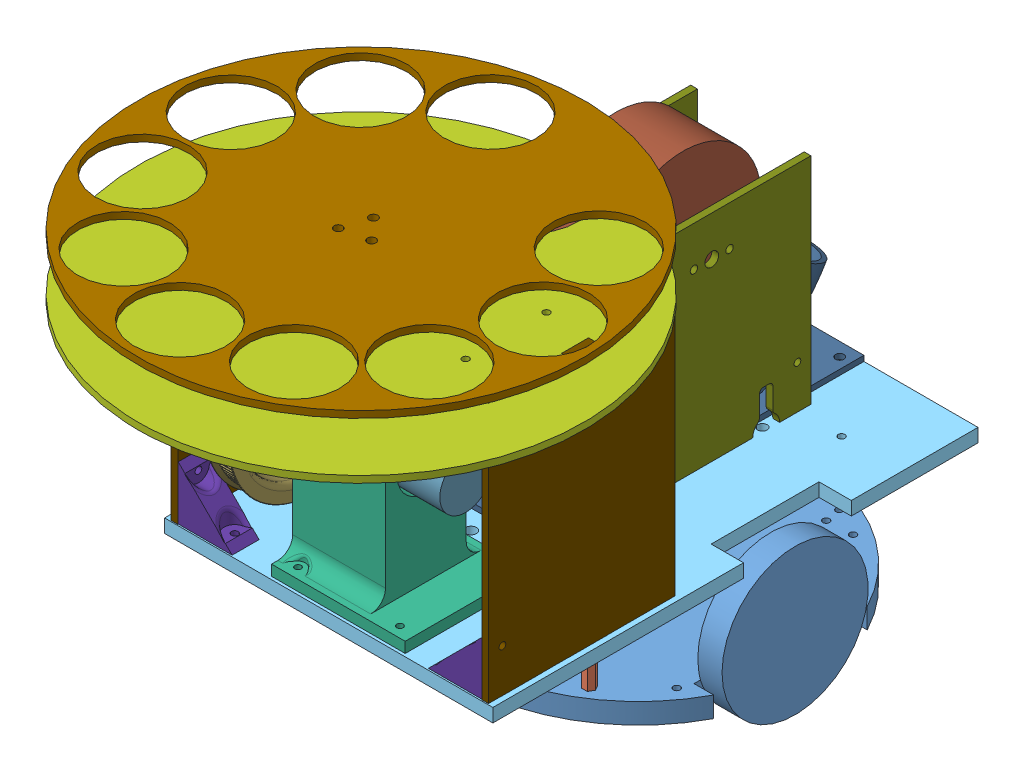
SolidWorks assembly car_and_shooter_assem, configuration Default. Lengths in mm.
Overall size (250.24 223.88 338.47).
32 component instances, 19 part files, 49 mates.
Components (placement in the parent):
- RSLKAss-1: RSLKAss [Default] at (33.1567 -8.9393 20.9388) size (154.69 155.83 228.6)
  - RSLKRobot-1: RSLKRobot [Default] at (-48.6373 76.7378 171.8377) size (153.54 68.83 162.51)
  - 1inHexSpacer-1: 1inHexSpacer [Default] at (-16.032 111.7898 197.7688) x (0.5 0 0.866025) z (0.866025 0 -0.5) size (5.57 31.75 4.83)
  - 1inHexSpacer-3: 1inHexSpacer [Default] at (67.9824 111.7898 197.7688) x (0.5 0 0.866025) z (0.866025 0 -0.5) size (5.57 31.75 4.83)
  - .75inHexSpacer-1: .75inHexSpacer [Default] at (52.5182 129.7222 100.832) x (1 0 0) z (0 0 -1) size (5.57 25.4 4.83)
  - .75inHexSpacer-2: .75inHexSpacer [Default] at (-0.5678 129.7222 191.0274) x (1 0 0) z (0 0 -1) size (5.57 25.4 4.83)
  - .75inHexSpacer-3: .75inHexSpacer [Default] at (52.5182 129.7222 191.0274) x (1 0 0) z (0 0 -1) size (5.57 25.4 4.83)
  - .75inHexSpacer-4: .75inHexSpacer [Default] at (-0.5678 129.7222 100.832) x (1 0 0) z (0 0 -1) size (5.57 25.4 4.83)
  - 1inHexSpacer-4: 1inHexSpacer [Default] at (-2.6646 111.7898 204.6548) x (0.5 0 0.866025) z (0.866025 0 -0.5) size (5.57 31.75 4.83)
  - 1inHexSpacer-5: 1inHexSpacer [Default] at (54.615 111.7898 204.6548) x (0.5 0 0.866025) z (0.866025 0 -0.5) size (5.57 31.75 4.83)
  - RSLKSpacePlate-1: RSLKSpacePlate [Default] at (67.9824 114.9648 197.7688) x (-1 0 0) z (0 0 -1) size (108.14 17.78 33.54)
  - RSLKBasePlate-2: RSLKBasePlate [Default] at (-0.5678 129.7222 191.276) size (154.69 6.35 228.6)
  - MotorMount-1: MotorMount [Default] at (-2.3457 191.0722 248.282) x (0 -1 0) z (1 0 0) size (81 58 63)
- bottom_plate-1: bottom_plate [Default] at (59.1391 246.5129 284.3207) size (210 3.17 210)
- stepper_motor_shaft-1: stepper_motor_shaft [Default] at (59.1391 249.6879 284.3207) x (0.976606 0 -0.215035) z (0.215035 0 0.976606) size (25.4 23.32 25.4)
- top_plate-1: top_plate [Default] at (59.1391 273.0079 284.3207) x (0.976606 0 -0.215035) z (0.215035 0 0.976606) size (210 3.17 210)
- ramp2-1: ramp2 [Default] at (59.1391 152.5329 147.1707) x (-1 0 0) z (0 0 -1) size (49.78 107.95 158.24)
- new_flywheel-1: new_flywheel [Default] at (41.8991 209.6829 147.1707) x (1 0 0) z (0 0.924409 -0.381402) size (36.83 73.66 73.66)
- BigBeltPulley-1: BigBeltPulley [Default] at (12.9611 182.1329 269.2207) x (0 0.970698 -0.240304) z (0 -0.240304 -0.970698) size (80.29 17.85 80.29)
- SmallBeltPulley-1: SmallBeltPulley [Default] at (13.4611 209.6829 147.1707) x (0 -0.048317 0.998832) z (0 0.998832 0.048317) size (23.29 19.9 23.29)
- dc_motor-1: dc_motor [Default] at (93.3111 182.1329 269.2207) x (-1 0 0) z (0 -0.970698 0.240304) size (75 32.2 24.4)
- ball-1: ball [Default] at (57.6426 155.7751 129.0822) x (-0.965872 0.249129 -0.070899) z (-0.118817 -0.182919 0.975922) size (42.67 42.67 42.67)
- SideFrameRight-1: SideFrameRight [Default] at (87.7141 127.1329 278.7427) x (0 0 1) z (-1 0 0) size (139.7 107.81 3.17)
- SideFrameRight-2: SideFrameRight [Default] at (33.7391 127.1329 278.2347) x (0 0 1) z (-1 0 0) size (139.7 107.81 3.17)
- 90Support-1: 90Support [Default] at (30.5641 127.1329 240.1347) x (0 0 -1) z (0 -1 0) size (13.26 25.4 25.4)
- wood_panel-1: wood_panel [Default] at (-12.4961 127.1329 211.2041) x (-1 0 0) z (0 0 -1) size (3.17 128.91 87.88)
- wood_panel-2: wood_panel [Default] at (133.8841 127.1329 211.1533) x (-1 0 0) z (0 0 -1) size (3.17 128.91 87.88)
- 90Support-2: 90Support [Default] at (-12.4961 246.5129 241.9381) x (0 0 1) z (-1 0 0) size (13.26 25.4 25.4)
- 90Support-3: 90Support [Default] at (-12.4961 127.1329 286.1741) x (0 0 1) z (0 -1 0) size (13.26 25.4 25.4)
- 90Support-4: 90Support [Default] at (130.7091 246.5129 292.6873) x (0 0 -1) z (1 0 0) size (13.26 25.4 25.4)
- 90Support-5: 90Support [Default] at (130.7091 127.1329 298.8233) x (0 0 -1) z (0 -1 0) size (13.26 25.4 25.4)
- shaft_for_motor_qtr_in-1: shaft_for_motor_qtr_in [Default] at (10.4611 209.6829 147.1707) size (71.12 6.22 6.22)
Mates (geometry in assembly coordinates):
- Concentric1: concentric aligned: cylinder of stepper_motor_shaft-1 through (53.5136 273.0079 289.4606) axis (0 -1 0) radius 1.875; cylinder of top_plate-1 through (53.5136 276.1829 289.4606) axis (0 -1 0) radius 2
- Concentric2: concentric aligned: cylinder of stepper_motor_shaft-1 through (66.4031 273.0079 286.6226) axis (0 -1 0) radius 1.875; cylinder of top_plate-1 through (66.4031 276.1829 286.6226) axis (0 -1 0) radius 2
- Coincident1: coincident anti-aligned: plane of stepper_motor_shaft-1 through (59.1391 273.0079 284.3207) normal (0 1 0); plane of top_plate-1 through (59.1391 273.0079 284.3207) normal (0 -1 0)
- Concentric3: concentric aligned: cylinder of bottom_plate-1 through (59.1391 249.6879 284.3207) axis (0 -1 0) radius 5; cylinder of stepper_motor_shaft-1 through (59.1391 270.0079 284.3207) axis (0 -1 0) radius 4.5
- Coincident2: coincident anti-aligned: plane of bottom_plate-1 through (59.1391 249.6879 284.3207) normal (0 1 0); plane of stepper_motor_shaft-1 through (59.1391 249.6879 284.3207) normal (0 -1 0)
- Coincident4: coincident anti-aligned: plane of RSLKAss-1/RSLKBasePlate-2 through (32.5889 127.1329 212.2148) normal (0 1 0); plane of ramp2-1 through (59.1391 127.1329 147.1707) normal (0 -1 0)
- Parallel2: parallel aligned: plane of RSLKAss-1/RSLKBasePlate-2 through (-18.2111 127.1329 70.9707) normal (0 0 -1); plane of ramp2-1 through (83.9991 127.1329 70.9707) normal (0 0 -1)
- Concentric4: concentric aligned: cylinder of bottom_plate-1 through (59.1391 249.6879 204.3207) axis (0 -1 0) radius 21.75; circle of ramp2-1
- Concentric5: concentric anti-aligned: circle of ramp2-1; cylinder of new_flywheel-1 through (80.7611 209.6829 147.1707) axis (-1 0 0) radius 36.83
- Distance1: distance = 7.62 mm: point of ramp2-1; plane of new_flywheel-1 through (41.8991 209.6829 147.1707) normal (-1 0 0)
- Concentric6: concentric aligned: cylinder of new_flywheel-1 through (80.7611 209.6829 147.1707) axis (-1 0 0) radius 36.83; cylinder of SmallBeltPulley-1 through (30.3611 209.6829 147.1707) axis (-1 0 0) radius 6.35
- Concentric7: concentric aligned: cylinder of RSLKAss-1/MotorMount-1 through (93.8111 182.1329 269.2207) axis (-1 0 0) radius 13.5; cylinder of BigBeltPulley-1 through (28.3111 182.1329 269.2207) axis (-1 0 0) radius 7.5
- Coincident5: coincident aligned: plane of BigBeltPulley-1 through (10.4611 182.1329 269.2207) normal (-1 0 0); plane of SmallBeltPulley-1 through (10.4611 209.6829 147.1707) normal (-1 0 0)
- Concentric8: concentric anti-aligned: cylinder of RSLKAss-1/MotorMount-1 through (93.8111 182.1329 269.2207) axis (-1 0 0) radius 13.5; cylinder of dc_motor-1 through (30.8111 182.1329 269.2207) axis (1 0 0) radius 12.2
- Coincident6: coincident aligned: plane of RSLKAss-1/MotorMount-1 through (30.8111 182.1329 269.2207) normal (-1 0 0); plane of dc_motor-1 through (30.8111 182.1329 269.2207) normal (-1 0 0)
- Parallel3: parallel anti-aligned: plane of BigBeltPulley-1 through (10.4611 183.0628 267.3937) normal (0 0.240304 0.970698); plane of dc_motor-1 through (18.3111 180.4884 268.0826) normal (0 -0.240304 -0.970698)
- Tangent1: tangent anti-aligned: torus of ramp2-1; sphere of ball-1
- Coincident7: coincident anti-aligned: plane of RSLKAss-1/RSLKBasePlate-2 through (84.5391 118.8779 202.5427) normal (0 0 -1); plane of SideFrameRight-1 through (84.5391 127.1329 202.5427) normal (0 0 1)
- Coincident8: coincident anti-aligned: plane of RSLKAss-1/RSLKBasePlate-2 through (32.5889 127.1329 212.2148) normal (0 1 0); plane of SideFrameRight-1 through (84.5391 127.1329 278.7427) normal (0 -1 0)
- Coincident9: coincident anti-aligned: plane of RSLKAss-1/RSLKBasePlate-2 through (84.5391 118.8779 184.0007) normal (1 0 0); plane of SideFrameRight-1 through (84.5391 127.1329 278.7427) normal (-1 0 0)
- Coincident10: coincident anti-aligned: plane of RSLKAss-1/RSLKBasePlate-2 through (30.6911 118.8779 202.0347) normal (0 0 -1); plane of SideFrameRight-2 through (30.5641 127.1329 202.0347) normal (0 0 1)
- Coincident11: coincident anti-aligned: plane of RSLKAss-1/RSLKBasePlate-2 through (32.5889 127.1329 212.2148) normal (0 1 0); plane of SideFrameRight-2 through (30.5641 127.1329 278.2347) normal (0 -1 0)
- Coincident12: coincident anti-aligned: plane of RSLKAss-1/RSLKBasePlate-2 through (33.7391 118.8779 202.0347) normal (-1 0 0); plane of SideFrameRight-2 through (33.7391 127.1329 278.2347) normal (1 0 0)
- Concentric9: concentric anti-aligned: cylinder of SideFrameRight-2 through (26.1191 147.4529 233.7847) axis (1 0 0) radius 1.5875; cylinder of 90Support-1 through (46.4391 147.4529 233.7847) axis (-1 0 0) radius 1.5875
- Coincident13: coincident anti-aligned: plane of RSLKAss-1/RSLKBasePlate-2 through (32.5889 127.1329 212.2148) normal (0 1 0); plane of 90Support-1 through (30.5641 127.1329 227.4347) normal (0 -1 0)
- Coincident14: coincident anti-aligned: plane of SideFrameRight-2 through (30.5641 127.1329 278.2347) normal (-1 0 0); plane of 90Support-1 through (30.5641 127.1329 227.4347) normal (1 0 0)
- Coincident16: coincident anti-aligned: plane of BigBeltPulley-1 through (28.3111 182.1329 269.2207) normal (1 0 0); plane of dc_motor-1 through (28.3111 182.1329 269.2207) normal (-1 0 0)
- Coincident17: coincident aligned: plane of RSLKAss-1/RSLKBasePlate-2 through (-18.2111 127.1329 70.9707) normal (0 0 -1); plane of ramp2-1 through (83.9991 127.1329 70.9707) normal (0 0 -1)
- Coincident18: coincident anti-aligned: plane of RSLKAss-1/RSLKBasePlate-2 through (-15.6711 120.7829 292.7127) normal (0 0 -1); plane of wood_panel-1 through (-15.6711 127.1329 292.7127) normal (0 0 1)
- Coincident19: coincident anti-aligned: plane of RSLKAss-1/RSLKBasePlate-2 through (-15.6711 120.7829 274.1707) normal (1 0 0); plane of wood_panel-1 through (-15.6711 127.1329 211.2041) normal (-1 0 0)
- Coincident20: coincident anti-aligned: plane of RSLKAss-1/RSLKBasePlate-2 through (32.5889 127.1329 212.2148) normal (0 1 0); plane of wood_panel-1 through (-15.6711 127.1329 211.2041) normal (0 -1 0)
- Coincident21: coincident anti-aligned: plane of RSLKAss-1/RSLKBasePlate-2 through (133.9349 120.7829 242.9287) normal (0 0 1); plane of wood_panel-2 through (130.7091 127.1329 242.9287) normal (0 0 -1)
- Coincident22: coincident anti-aligned: plane of RSLKAss-1/RSLKBasePlate-2 through (130.7091 120.7829 242.9287) normal (1 0 0); plane of wood_panel-2 through (130.7091 127.1329 211.1533) normal (-1 0 0)
- Coincident23: coincident anti-aligned: plane of RSLKAss-1/RSLKBasePlate-2 through (32.5889 127.1329 212.2148) normal (0 1 0); plane of wood_panel-2 through (130.7091 127.1329 292.6619) normal (0 -1 0)
- Concentric10: concentric anti-aligned: cylinder of wood_panel-1 through (-12.4961 226.1929 248.2881) axis (-1 0 0) radius 1.5875; cylinder of 90Support-2 through (-28.3711 226.1929 248.2881) axis (1 0 0) radius 1.5875
- Coincident24: coincident anti-aligned: plane of wood_panel-1 through (-12.4961 127.1329 211.2041) normal (1 0 0); plane of 90Support-2 through (-12.4961 246.5129 254.6381) normal (-1 0 0)
- Parallel4: parallel aligned: plane of wood_panel-1 through (-15.6711 249.6879 299.0881) normal (0 0 1); plane of 90Support-2 through (-12.4961 246.5129 254.6381) normal (0 0 1)
- Concentric13: concentric aligned: cylinder of wood_panel-2 through (133.8841 226.1929 286.3373) axis (-1 0 0) radius 1.5875; cylinder of 90Support-4 through (146.5841 226.1929 286.3373) axis (-1 0 0) radius 1.5875
- Coincident25: coincident anti-aligned: plane of wood_panel-2 through (130.7091 127.1329 211.1533) normal (-1 0 0); plane of 90Support-4 through (130.7091 246.5129 279.9873) normal (1 0 0)
- Coincident26: coincident anti-aligned: plane of bottom_plate-1 through (59.1391 246.5129 284.3207) normal (0 -1 0); plane of 90Support-4 through (130.7091 246.5129 279.9873) normal (0 1 0)
- Coincident28: coincident anti-aligned: plane of RSLKAss-1/RSLKBasePlate-2 through (32.5889 127.1329 212.2148) normal (0 1 0); plane of 90Support-3 through (-12.4961 127.1329 298.8741) normal (0 -1 0)
- Coincident29: coincident anti-aligned: plane of wood_panel-1 through (-12.4961 127.1329 211.2041) normal (1 0 0); plane of 90Support-3 through (-12.4961 127.1329 298.8741) normal (-1 0 0)
- Coincident30: coincident anti-aligned: plane of RSLKAss-1/RSLKBasePlate-2 through (32.5889 127.1329 212.2148) normal (0 1 0); plane of 90Support-5 through (130.7091 127.1329 286.1233) normal (0 -1 0)
- Coincident31: coincident anti-aligned: plane of wood_panel-2 through (130.7091 127.1329 211.1533) normal (-1 0 0); plane of 90Support-5 through (130.7091 127.1329 286.1233) normal (1 0 0)
- Concentric16: concentric anti-aligned: cylinder of wood_panel-2 through (130.7091 147.4529 292.4733) axis (1 0 0) radius 1.5875; cylinder of 90Support-5 through (146.5841 147.4529 292.4733) axis (-1 0 0) radius 1.5875
- Distance2: distance = 1.81 mm anti-aligned: plane of ramp2-1 through (35.5491 130.1809 70.9707) normal (-1 0 0); plane of SideFrameRight-2 through (33.7391 127.1329 278.2347) normal (1 0 0)
- Parallel6: parallel anti-aligned: plane of bottom_plate-1 through (133.9161 246.5129 299.0796) normal (0 0 -1); plane of wood_panel-2 through (130.7091 249.6879 299.0373) normal (0 0 1)
- Concentric17: concentric anti-aligned: cylinder of SmallBeltPulley-1 through (10.4611 209.6829 147.1707) axis (1 0 0) radius 3.188; cylinder of shaft_for_motor_qtr_in-1 through (56.1129 209.6829 147.1707) axis (-1 0 0) radius 3.1115
- Coincident32: coincident aligned: plane of SmallBeltPulley-1 through (10.4611 209.6829 147.1707) normal (-1 0 0); plane of shaft_for_motor_qtr_in-1 through (-15.0071 209.6829 147.1707) normal (-1 0 0)
